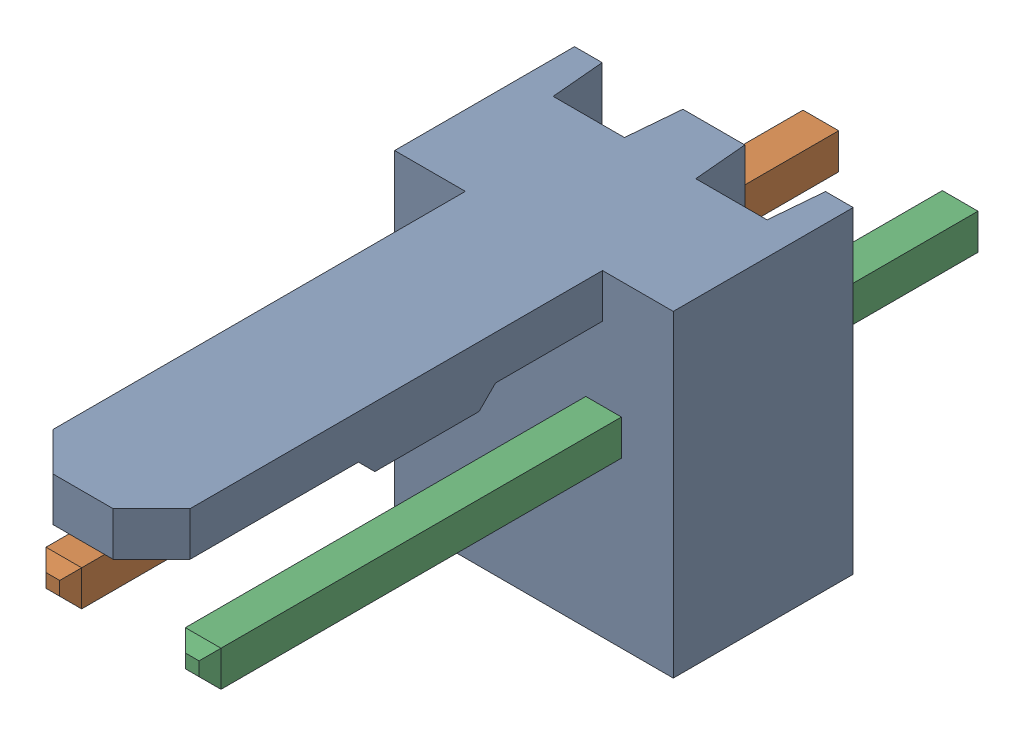
SolidWorks assembly Molex PCB 2 pin v2_4, configuration Predeterminado. Lengths in mm.
Overall size (5.08 5.79 14.92).
3 component instances, 2 part files, 0 mates.
Components (placement in the parent):
- BASE9710016_1-1: BASE9710016_1 [Predeterminado] at (2.54 2.895 -8.22) size (5.08 5.79 11.5)
- PINO9710016_1-1: PINO9710016_1 [Predeterminado] at (1.27 3.325 -0.72) size (0.65 0.65 14.2)
- PINO9710016_1-2: PINO9710016_1 [Predeterminado] at (3.81 3.325 -0.72) size (0.65 0.65 14.2)
